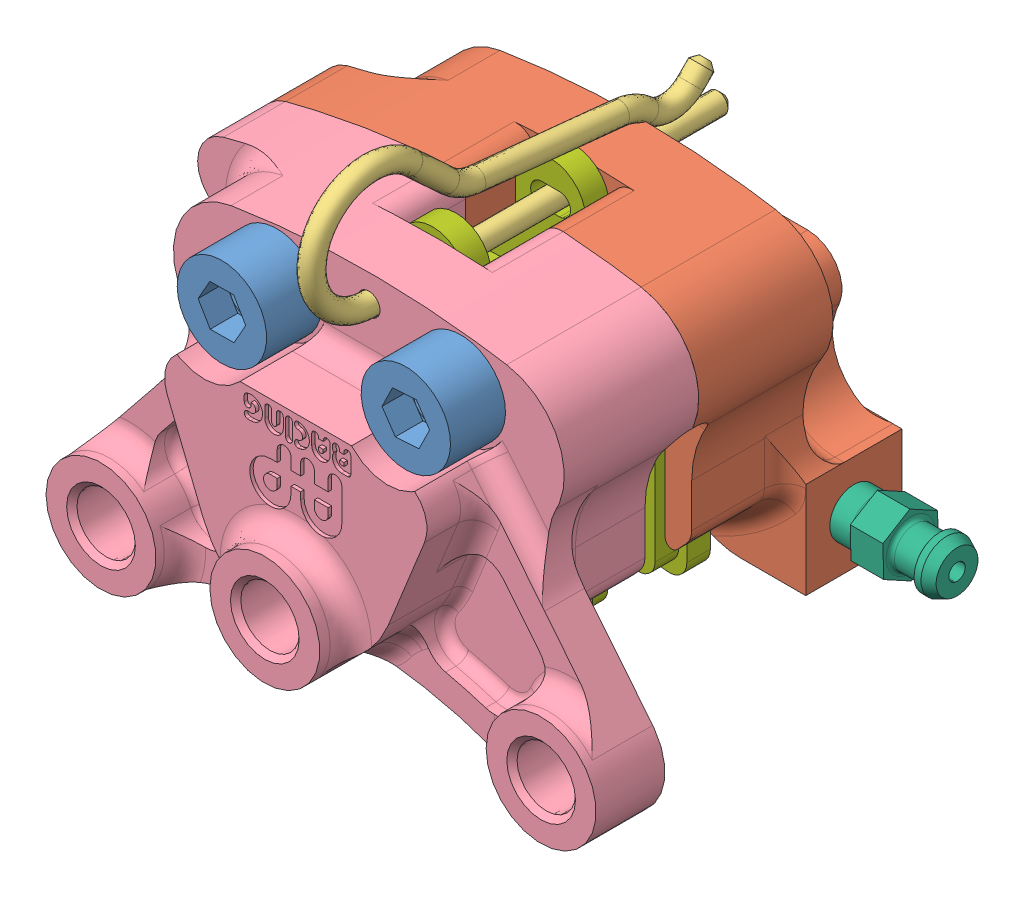
SolidWorks assembly BR-A0102-AA-Caliper Assembly, configuration Default. Lengths in mm.
Overall size (40.11 43.54 52.73).
10 component instances, 7 part files, 6 mates.
Components (placement in the parent):
- cp3838-M08x1.25m_CP4477-110^BR-A0102-AA-Caliper Assembly-1: cp3838-M08x1.25m_CP4477-110^BR-A0102-AA-Caliper Assembly [Default] at (-13.37 19.3 19.55) x (-0.999952 -0.009843 0) z (0 0 -1) size (13 13 46) (virtual)
- CP4226-102^BR-A0102-AA-Caliper Assembly-1: CP4226-102^BR-A0102-AA-Caliper Assembly [Default] x (-1 0 0) z (0 0 -1) size (63.87 47.42 31.57) (virtual)
- cp4226-104_CP4226-104^BR-A0102-AA-Caliper Assembly-1: cp4226-104_CP4226-104^BR-A0102-AA-Caliper Assembly [Default] at (0 23 -31.9644) x (0 0 1) z (-1 0 0) size (61.35 20.1 3) (virtual)
- CP4226-101^BR-A0102-AA-Caliper Assembly-1: CP4226-101^BR-A0102-AA-Caliper Assembly [Default] at origin size (81.26 55.69 34.68) (virtual)
- cp3838-M08x1.25m_CP4477-110^BR-A0102-AA-Caliper Assembly-2: cp3838-M08x1.25m_CP4477-110^BR-A0102-AA-Caliper Assembly [Default] at (13.37 19.3 19.55) x (-0.997666 -0.068288 0) z (0 0 -1) size (13 13 46) (virtual)
- cp3049-40a_CP4226-103^BR-A0102-AA-Caliper Assembly-1: cp3049-40a_CP4226-103^BR-A0102-AA-Caliper Assembly [Default] at (0 0 10.305) x (-0.993137 0.116957 0) z (0 0 -1) size (25.2 25.2 14.87) (virtual)
- CP4469-101^BR-A0102-AA-Caliper Assembly-1: CP4469-101^BR-A0102-AA-Caliper Assembly [Default] at (42 -11.5 -23.98) x (0 -0.520643 0.853775) z (-1 0 0) size (9.18 8.2 29.15) (virtual)
- cp3049-40a_CP4226-103^BR-A0102-AA-Caliper Assembly-2: cp3049-40a_CP4226-103^BR-A0102-AA-Caliper Assembly [Default] at (0 0 -10.305) size (25.2 25.2 14.87) (virtual)
- Brake Pad^BR-A0102-AA-Caliper Assembly-1: Brake Pad^BR-A0102-AA-Caliper Assembly [Default] at (0 11.1798 8.5855) x (-1 0 0) z (0 -1 0) size (39.62 6.86 43.54) (virtual)
- Brake Pad^BR-A0102-AA-Caliper Assembly-2: Brake Pad^BR-A0102-AA-Caliper Assembly [Default] at (0 11.1798 -8.5905) x (1 0 0) z (0 -1 0) size (39.62 6.86 43.54) (virtual)
Mates (geometry in assembly coordinates):
- Coincident3: coincident anti-aligned: plane of Brake Pad-1 through (0 11.1798 8.5855) normal (-1 0 0); plane of assembly through (0 0 0) normal (1 0 0)
- Coincident6: coincident anti-aligned: plane of Brake Pad-1 through (0 23 8.5855) normal (0 1 0); plane of assembly through (0 23 0) normal (0 -1 0)
- Coincident7: coincident anti-aligned: plane of CP4226-101^BR-A0102-AA-Caliper Assembly-1 through (8.5 17.48 10.3) normal (0 0 -1); plane of Brake Pad-1 through (0 -141.2681 10.3) normal (0 0 1)
- Coincident8: coincident anti-aligned: plane of cp3049-40a_CP4226-103-2 through (0 7.8225 -10.305) normal (0 0 1); plane of Brake Pad-2 through (0 -141.2681 -10.305) normal (0 0 -1)
- Concentric1: concentric anti-aligned: cylinder of Brake Pad-1 through (0 -141.2681 6.871) axis (0 0 1) radius 127; cylinder of Brake Pad-2 through (0 -141.2681 -6.876) axis (0 0 -1) radius 127
- Parallel1: parallel aligned: plane of Brake Pad-1 through (19.812 -15.823 6.871) normal (1 0 0); plane of Brake Pad-2 through (19.812 -15.823 -6.876) normal (1 0 0)
